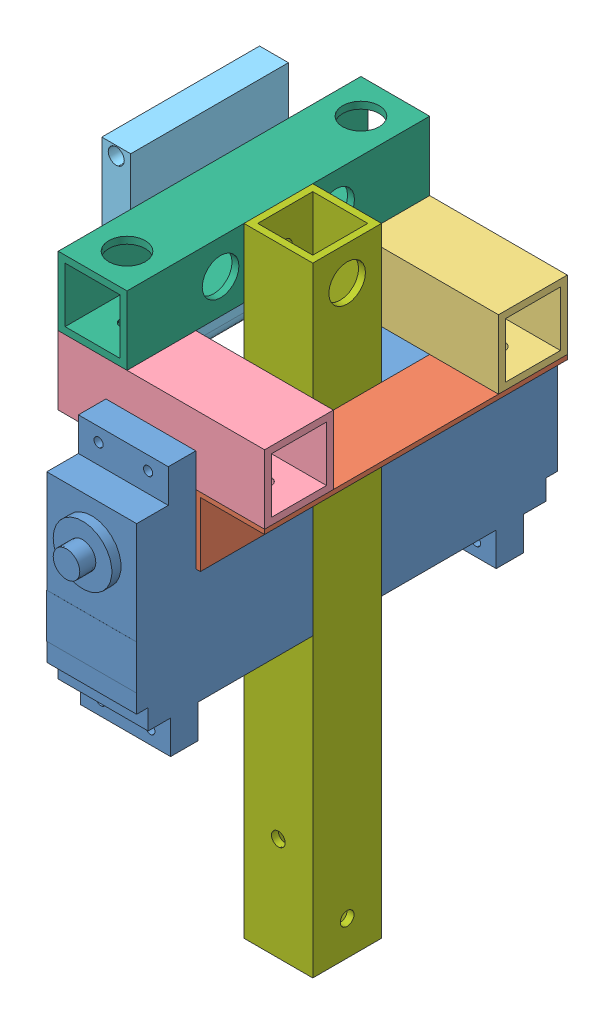
SolidWorks assembly 上, configuration ﾃﾞﾌｫﾙﾄ. Lengths in mm.
Overall size (51.3 210.5 102.8).
8 component instances, 7 part files, 14 mates.
Components (placement in the parent):
- サーボ_MG995-1: サーボ_MG995 [ﾃﾞﾌｫﾙﾄ] at (-26.3696 3.9678 33.05) size (19.6 55 43.9)
- 肩固定_伸ばし-2: 肩固定_伸ばし [ﾃﾞﾌｫﾙﾄ] at (14.5564 15.7443 58.5498) x (1 0 0) z (0 0 -1) size (15 15 66)
- 肩固定_サーボ_右-1: 肩固定_サーボ_右 [ﾃﾞﾌｫﾙﾄ] at (-20.905 31.6584 0.5398) x (0 0 -1) z (1 0 0) size (15 15 45)
- 肩固定_サーボ_左-1: 肩固定_サーボ_左 [ﾃﾞﾌｫﾙﾄ] at (-20.905 31.6584 51.5398) x (0 0 -1) z (1 0 0) size (15 15 45)
- サーボ_MG995-2: サーボ_MG995 [ﾃﾞﾌｫﾙﾄ] at (24.9596 3.9678 18.0497) x (-1 0 0) z (0 0 -1) size (19.6 55 43.9)
- カメラ-1: カメラ [ﾃﾞﾌｫﾙﾄ] at (-27.205 53.4733 28.539) size (6.3 45.5 34.4)
- 肩固定_伸ばし_前-1: 肩固定_伸ばし_前 [ﾃﾞﾌｫﾙﾄ] at (-13.8949 46.6584 -7.4502) size (15 15 66)
- 肩固定_支柱-1: 肩固定_支柱 [ﾃﾞﾌｫﾙﾄ] at (1.8276 54.391 25.0599) x (0 0 1) z (0 -1 0) size (15 15 200)
Mates (geometry in assembly coordinates):
- 一致9: coincident aligned: circle of 肩固定_伸ばし-2; circle of 肩固定_サーボ_右-1
- 一致10: coincident aligned: circle of 肩固定_伸ばし-2; circle of 肩固定_サーボ_左-1
- 一致11: coincident aligned: circle of サーボ_MG995-1; circle of 肩固定_サーボ_左-1
- 一致12: coincident aligned: circle of サーボ_MG995-1; circle of 肩固定_サーボ_左-1
- 一致14: coincident aligned: circle of 肩固定_サーボ_右-1; circle of サーボ_MG995-2
- 一致15: coincident aligned: circle of 肩固定_サーボ_右-1; circle of サーボ_MG995-2
- 一致16: coincident anti-aligned: circle of 肩固定_サーボ_右-1; circle of 肩固定_伸ばし_前-1
- 一致17: coincident anti-aligned: circle of 肩固定_サーボ_左-1; circle of 肩固定_伸ばし_前-1
- 一致18: coincident anti-aligned: circle of カメラ-1; circle of 肩固定_伸ばし_前-1
- 一致19: coincident anti-aligned: circle of カメラ-1; circle of 肩固定_伸ばし_前-1
- 一致21: coincident anti-aligned: circle of 肩固定_伸ばし_前-1; circle of 肩固定_支柱-1
- 一致22: coincident aligned: circle of 肩固定_伸ばし-2; circle of 肩固定_支柱-1
- 一致23: coincident anti-aligned: plane of サーボ_MG995-1 through (-26.3696 3.9678 33.05) normal (0 0 -1); plane of 肩固定_支柱-1 through (-5.905 -145.609 33.0498) normal (0 0 1)
- 一致24: coincident anti-aligned: plane of サーボ_MG995-2 through (24.9596 3.9678 18.0497) normal (0 0 1); plane of 肩固定_支柱-1 through (-5.905 -145.609 18.0498) normal (0 0 -1)
